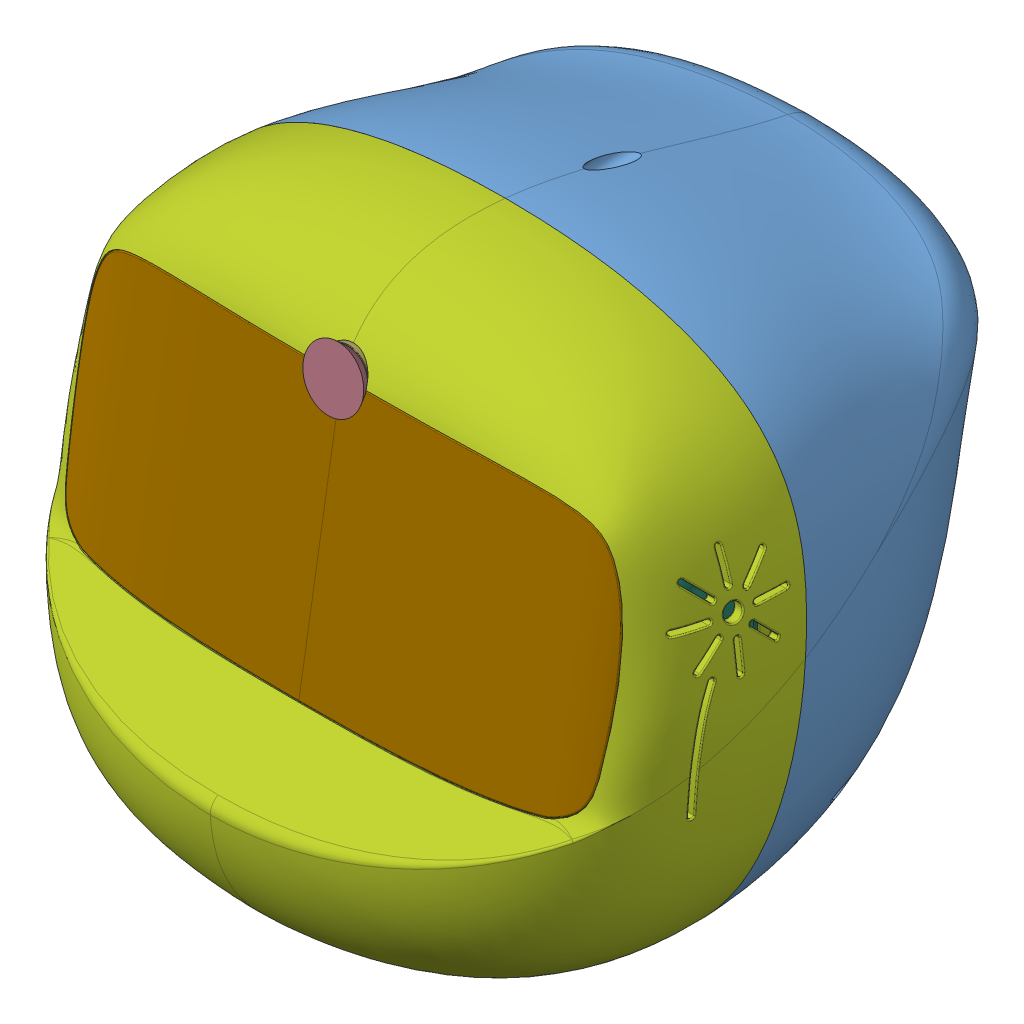
SolidWorks assembly head, configuration Défaut. Lengths in mm.
Overall size (161.82 129.81 135.97).
21 component instances, 18 part files, 41 mates.
Components (placement in the parent):
- head_back-1: head_back [Default] at origin size (139.97 128.52 115.71)
- AX-12_18A-1: AX-12_18A [Défaut] x (0 0.939693 0.34202) z (1 0 0) size (32 50.04 40.32)
  - dynamixel_AXseries-1: dynamixel_AXseries [Défaut] at origin size (32 50.04 38.37)
  - AX12_horn-1: AX12_horn [Défaut] at (0 0 19.1) x (0 1 0) z (0 0 1) size (22 22 6.7)
  - BHS_M2_6X8-1: BHS_M2_6X8 [Défaut] at (0 0 19.55) x (0.628847 -0.777529 0) z (-0.777529 -0.628847 0) size (5.5 9.6 5.5)
- Odroid XU4-1: Odroid XU4 [Default] at (-2.6425 63.323 -42.277) x (1 0 0) z (0 -0.087156 -0.996195) size (83 24.75 59)
- fake_manga_screen-1: fake_manga_screen [Default] at (0 46.1109 21.48) x (1 0 0) z (0 0.162719 0.986672) size (106 70.75 3.7)
- head_face-1: head_face [Default] at origin size (139.72 119.1 102)
- screen_support-1: screen_support [Default] at origin size (119.01 63.24 19.97)
- screen-1: screen [Default] at origin size (152.35 100.2 22.24)
- Videw_JDEPC-OV04-2: Videw_JDEPC-OV04 [170_FOV_lens] at (0 79.5531 9.1743) x (1 0 0) z (0 0.162719 0.986672) size (60.45 12.74 14.53)
  - Videw_JDEPC-OV04-1: Videw_JDEPC-OV04 [Défaut] at origin size (60 8 0.6)
  - SM05B-SRSS-TB-1: SM05B-SRSS-TB [Default] at (-23.7 0 0.6) x (0 -1 0) z (-1 0 0) size (7 2.9 4.95)
  - 170_FOV_lens-1: 170_FOV_lens [Défaut] at (0 0 0.6) size (10 10 12.3)
  - 65_FOV_lens-1: 65_FOV_lens [Défaut] at (0 0 0.6) size (12.74 12.74 13.93)
- camera_support-1: camera_support [Default] at (0 0.0163 0.0987) size (81.74 18.94 5.38)
- VisatonK20.40_speaker-2: VisatonK20.40_speaker [Défaut] at (-59.643 48.4618 4.5746) x (-0.088219 -0.989732 0.112468) z (-0.984948 0.103522 0.138425) size (40 20 7.34)
- VisatonK20.40_speaker-1: VisatonK20.40_speaker [Défaut] at (59.643 48.4618 4.5746) x (0.088219 -0.989732 0.112468) z (0.984948 0.103522 0.138425) size (40 20 7.34)
- speaker_left-1: speaker_left [Default] at origin size (22.54 62.27 50.74)
- speaker_right-1: speaker_right [Default] at origin size (22.54 62.27 50.74)
- 9DOF-Razor-v23-1: 9DOF-Razor-v23 [Default] at (0 23.915 -2) size (41 7.1 28)
Mates (geometry in assembly coordinates):
- Coincident1: coincident aligned: line of AX-12_18A-1/dynamixel_AXseries-1 through (-31.6133 0 0) axis (1 0 0)
- Coincident25: coincident aligned: plane of AX-12_18A-1/dynamixel_AXseries-1 through (0 0 0) normal (1 0 0); plane of assembly through (0 0 0) normal (1 0 0)
- Coincident34: coincident aligned: plane of head_back-1 through (0 0 0) normal (0 0 1); plane of assembly through (0 0 0) normal (0 0 1)
- Coincident35: coincident aligned: plane of head_back-1 through (0 0 0) normal (1 0 0); plane of assembly through (0 0 0) normal (1 0 0)
- Coincident36: coincident aligned: plane of head_back-1 through (0 0 0) normal (0 1 0); plane of assembly through (0 0 0) normal (0 1 0)
- Coincident38: coincident aligned: plane of head_face-1 through (0 0 0) normal (1 0 0); plane of assembly through (0 0 0) normal (1 0 0)
- Coincident39: coincident aligned: plane of head_face-1 through (0 0 0) normal (1 0 0); plane of screen-1 through (0 0 0) normal (1 0 0)
- Coincident40: coincident aligned: plane of head_face-1 through (0 0 0) normal (0 1 0); plane of screen-1 through (0 0 0) normal (0 1 0)
- Coincident41: coincident aligned: plane of head_face-1 through (0 0 0) normal (0 0 1); plane of screen-1 through (0 0 0) normal (0 0 1)
- Coincident45: coincident aligned: plane of head_face-1 through (0 0 0) normal (0 0 1); plane of screen_support-1 through (0 0 0) normal (0 0 1)
- Coincident46: coincident aligned: plane of head_face-1 through (0 0 0) normal (0 1 0); plane of screen_support-1 through (0 0 0) normal (0 1 0)
- Coincident47: coincident aligned: plane of head_face-1 through (0 0 0) normal (1 0 0); plane of screen_support-1 through (0 0 0) normal (1 0 0)
- Concentric1: concentric aligned: cylinder of AX-12_18A-1/dynamixel_AXseries-1 through (16 14.909 -1.4907) axis (1 0 0) radius 1.1; cylinder of head_back-1 through (26 14.909 -1.4907) axis (1 0 0) radius 1.1
- Concentric4: concentric anti-aligned: cylinder of fake_manga_screen-1 through (46.5 -9.8873 -96.8341) axis (0 0.162719 0.986672) radius 1.5; cylinder of head_face-1 through (46.5 10.2328 25.1672) axis (0 -0.162719 -0.986672) radius 1.35
- Coincident49: coincident anti-aligned: plane of fake_manga_screen-1 through (-46.5 10.2328 25.1672) normal (0 0.162719 0.986672); plane of head_face-1 through (46.5 10.2328 25.1672) normal (0 -0.162719 -0.986672)
- Concentric5: concentric aligned: cylinder of head_face-1 through (20 86.6987 12.5567) axis (0 -0.162719 -0.986672) radius 1.35; cylinder of camera_support-1 through (20 86.3733 10.5833) axis (0 -0.162719 -0.986672) radius 1.15
- Concentric6: concentric aligned: cylinder of head_face-1 through (-20 86.6987 12.5567) axis (0 -0.162719 -0.986672) radius 1.35; cylinder of camera_support-1 through (-20 86.3733 10.5833) axis (0 -0.162719 -0.986672) radius 1.15
- Coincident50: coincident anti-aligned: plane of head_face-1 through (-20 86.6987 12.5567) normal (0 -0.162719 -0.986672); plane of camera_support-1 through (20 86.6987 12.5567) normal (0 0.162719 0.986672)
- Concentric7: concentric aligned: cylinder of Videw_JDEPC-OV04-2/Videw_JDEPC-OV04-1 through (31 81.5007 9.4612) axis (0 -0.162719 -0.986672) radius 1; cylinder of camera_support-1 through (31 81.5007 9.4612) axis (0 -0.162719 -0.986672) radius 1.1
- Concentric8: concentric aligned: cylinder of Videw_JDEPC-OV04-2/Videw_JDEPC-OV04-1 through (-19.75 77.8007 10.0714) axis (0 -0.162719 -0.986672) radius 1; cylinder of camera_support-1 through (-19.75 77.8007 10.0714) axis (0 -0.162719 -0.986672) radius 1.1
- Coincident51: coincident anti-aligned: plane of Videw_JDEPC-OV04-2/Videw_JDEPC-OV04-1 through (0 79.6507 9.7663) normal (0 0.162719 0.986672); plane of camera_support-1 through (0 3.6769 22.2957) normal (0 -0.162719 -0.986672)
- Concentric9: concentric aligned: cylinder of head_face-1 through (57.2743 65.2814 -5.5984) axis (0.984948 0.103522 0.138425) radius 1; cylinder of VisatonK20.40_speaker-1 through (59.2442 65.4884 -5.3215) axis (0.984948 0.103522 0.138425) radius 1.1
- Concentric10: concentric aligned: cylinder of head_face-1 through (58.0719 31.2281 14.1939) axis (0.984948 0.103522 0.138425) radius 1; cylinder of VisatonK20.40_speaker-1 through (60.0418 31.4351 14.4708) axis (0.984948 0.103522 0.138425) radius 1.1
- Coincident52: coincident anti-aligned: plane of head_face-1 through (62.4201 29.8581 -1.2727) normal (-0.984948 -0.103522 -0.138425); plane of VisatonK20.40_speaker-1 through (59.643 48.4618 4.5746) normal (0.984948 0.103522 0.138425)
- Concentric11: concentric anti-aligned: cylinder of head_face-1 through (36.0744 71.9587 -1.3395) axis (0.984948 0.103522 0.138425) radius 1.1; cylinder of speaker_left-1 through (86.137 77.2205 5.6963) axis (-0.984948 -0.103522 -0.138425) radius 1.1
- Concentric12: concentric anti-aligned: cylinder of head_face-1 through (40.6618 20.4927 4.5088) axis (0.984948 0.103522 0.138425) radius 1.1; cylinder of speaker_left-1 through (90.7244 25.7545 11.5447) axis (-0.984948 -0.103522 -0.138425) radius 1.1
- Coincident53: coincident anti-aligned: plane of head_face-1 through (54.3945 73.8842 1.2352) normal (-0.984948 -0.103522 -0.138425); plane of speaker_left-1 through (54.3945 73.8842 1.2352) normal (0.984948 0.103522 0.138425)
- Concentric13: concentric aligned: cylinder of head_face-1 through (-57.2743 65.2814 -5.5984) axis (-0.984948 0.103522 0.138425) radius 1; cylinder of VisatonK20.40_speaker-2 through (-59.2442 65.4884 -5.3215) axis (-0.984948 0.103522 0.138425) radius 1.1
- Concentric14: concentric aligned: cylinder of head_face-1 through (-60.4502 29.6511 -1.5495) axis (-0.984948 0.103522 0.138425) radius 1; cylinder of VisatonK20.40_speaker-2 through (-62.4201 29.8581 -1.2727) axis (-0.984948 0.103522 0.138425) radius 1.1
- Coincident54: coincident anti-aligned: plane of head_face-1 through (-62.4201 29.8581 -1.2727) normal (0.984948 -0.103522 -0.138425); plane of VisatonK20.40_speaker-2 through (-59.643 48.4618 4.5746) normal (-0.984948 0.103522 0.138425)
- Concentric15: concentric anti-aligned: cylinder of head_face-1 through (-36.0744 71.9587 -1.3395) axis (-0.984948 0.103522 0.138425) radius 1.1; cylinder of speaker_right-1 through (-86.137 77.2205 5.6963) axis (0.984948 -0.103522 -0.138425) radius 1.1
- Concentric16: concentric anti-aligned: cylinder of head_face-1 through (-40.6618 20.4927 4.5088) axis (-0.984948 0.103522 0.138425) radius 1.1; cylinder of speaker_right-1 through (-90.7244 25.7545 11.5447) axis (0.984948 -0.103522 -0.138425) radius 1.1
- Coincident55: coincident anti-aligned: plane of head_face-1 through (-58.9818 22.4182 7.0835) normal (0.984948 -0.103522 -0.138425); plane of speaker_right-1 through (-54.3945 73.8842 1.2352) normal (-0.984948 0.103522 0.138425)
- Concentric17: concentric aligned: cylinder of head_face-1 through (0 92.7582 -42.9201) axis (0 0.061049 -0.998135) radius 1.15; cylinder of head_back-1 through (0 92.7582 -42.9201) axis (0 0.061049 -0.998135) radius 1.15
- Concentric18: concentric aligned: cylinder of head_face-1 through (58.5 9.5035 -33.9884) axis (0 -0.242495 -0.970153) radius 1.25; cylinder of head_back-1 through (58.5 9.5035 -33.9884) axis (0 -0.242495 -0.970153) radius 1.25
- Concentric19: concentric: cylinder of 9DOF-Razor-v23-1 through (17.78 25.515 9.43) axis (0 -1 0) radius 1.85; cylinder of head_back-1 through (17.78 25.515 9.43) axis (0 -1 0) radius 1.65
- Coincident56: coincident: plane of head_back-1 through (-17.78 23.915 9.43) normal (0 1 0); plane of 9DOF-Razor-v23-1 through (-1.8334 23.915 1.5503) normal (0 -1 0)
- Concentric20: concentric aligned: cylinder of 9DOF-Razor-v23-1 through (-17.78 25.515 -13.43) axis (0 -1 0) radius 1.85; cylinder of head_back-1 through (-17.78 26.415 -13.43) axis (0 -1 0) radius 1.65
- Concentric21: concentric: cylinder of head_back-1 through (-38 37.3094 -7.5439) axis (0 0.996195 -0.087156) radius 2; cylinder of Odroid XU4-1 through (-38 45.9333 -8.2983) axis (0 -0.996195 0.087156) radius 1.6
- Coincident57: coincident: plane of head_back-1 through (-38 44.9371 -8.2112) normal (0 0.996195 -0.087156); plane of Odroid XU4-1 through (38.5 44.9807 -7.7131) normal (0 -0.996195 0.087156)
- Concentric22: concentric aligned: cylinder of head_back-1 through (-38 46.8574 -60.5778) axis (0 -0.996195 0.087156) radius 1.3; cylinder of Odroid XU4-1 through (-38 41.4012 -60.1005) axis (0 -0.996195 0.087156) radius 1.6
